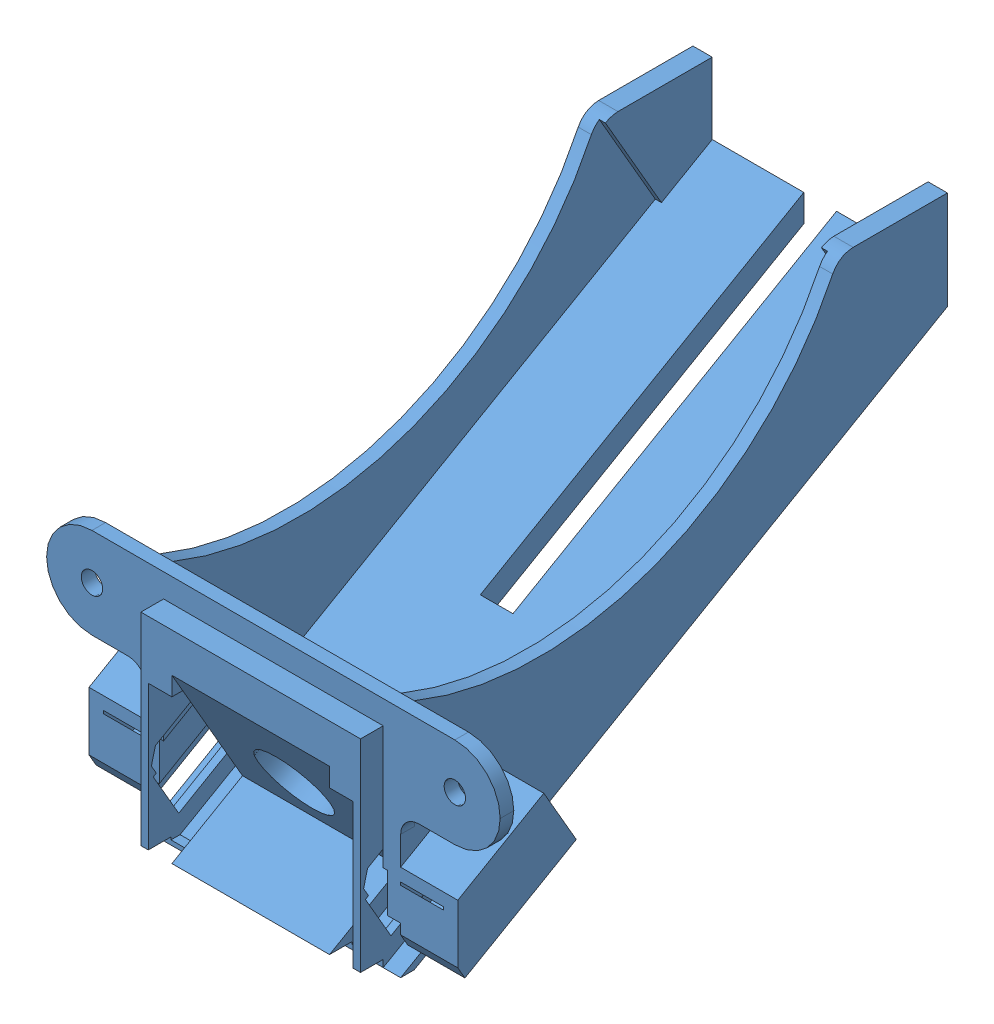
SolidWorks assembly bottleMountAssembly, configuration Default. Lengths in mm.
Overall size (63.5 56.87 79.72).
6 component instances, 5 part files, 12 mates.
Components (placement in the parent):
- bottle-1: bottle [Default] at (-0.6948 217.1065 -36.0917) x (0.0057 -0.258799 -0.965914) z (-0.999968 -0.006981 -0.00403) (suppressed, hidden)
- bottlePivot-1: bottlePivot [NewBottle] at (0.2137 47.0768 17.3511) x (-1 0 0) z (0 0.5 -0.866025) (suppressed, hidden)
- bottleMount-1: bottleMount [external_ir] at (0.2137 51.4957 48.6286) size (63.5 56.87 79.72)
- irOutline_sparkfun-3: irOutline_sparkfun [Default] at (-15.7593 31.9593 48.5354) x (0 0.866025 0.5) z (1 0 0) (suppressed, hidden)
- irOutline_sparkfun-4: irOutline_sparkfun [Default] at (16.1867 31.9593 48.5354) x (0 -0.866025 -0.5) z (-1 0 0) (suppressed, hidden)
- M3x12-1: M3x12 [90751A113] at (0.2137 70.9615 25.6416) x (-0.951128 0.154398 -0.267426) z (0 -0.866025 -0.5) (suppressed, hidden)
Mates (geometry in assembly coordinates):
- Coincident2: coincident anti-aligned: plane of bottlePivot-1 through (0.2137 51.8393 9.1022) normal (0 -0.866025 -0.5); plane of bottleMount-1 through (-14.8993 34.638 38.8958) normal (0 0.866025 0.5)
- Coincident3: coincident anti-aligned: plane of bottlePivot-1 through (-2.0723 48.6643 14.6015) normal (-1 0 0); plane of bottleMount-1 through (-2.0723 -0.5281 18.5926) normal (1 0 0)
- Coincident4: coincident anti-aligned: plane of bottleMount-1 through (-14.8993 34.638 38.8958) normal (0 0.866025 0.5); plane of irOutline_sparkfun-3 through (-11.4593 29.7942 47.2854) normal (0 -0.866025 -0.5)
- Coincident5: coincident anti-aligned: plane of bottleMount-1 through (0.2137 45.402 59.1833) normal (0 0.5 -0.866025); plane of irOutline_sparkfun-3 through (-11.4593 30.7093 50.7005) normal (0 -0.5 0.866025)
- Coincident6: coincident anti-aligned: plane of bottleMount-1 through (-15.7593 79.1474 -21.9031) normal (1 0 0); plane of irOutline_sparkfun-3 through (-15.7593 31.9593 48.5354) normal (-1 0 0)
- Coincident7: coincident anti-aligned: plane of bottleMount-1 through (-14.8993 34.638 38.8958) normal (0 0.866025 0.5); plane of irOutline_sparkfun-4 through (11.8867 29.7942 47.2854) normal (0 -0.866025 -0.5)
- Coincident8: coincident anti-aligned: plane of bottleMount-1 through (0.2137 45.402 59.1833) normal (0 0.5 -0.866025); plane of irOutline_sparkfun-4 through (11.8867 30.7093 50.7005) normal (0 -0.5 0.866025)
- Coincident9: coincident anti-aligned: plane of bottleMount-1 through (16.1867 79.1474 -21.9031) normal (-1 0 0); plane of irOutline_sparkfun-4 through (16.1867 31.9593 48.5354) normal (1 0 0)
- LimitDistance1: limit distance = 4.911 mm anti-aligned: plane of bottlePivot-1 through (-25.1863 35.3293 37.6984) normal (0 -0.5 0.866025); plane of irOutline_sparkfun-3 through (-11.4593 36.7093 40.3082) normal (0 0.5 -0.866025)
- Concentric1: concentric anti-aligned: cylinder of bottle-1 through (0.2137 38.6654 47.5801) axis (0 0.5 -0.866025) radius 5; cylinder of bottlePivot-1 through (0.2137 58.6203 13.0172) axis (0 -0.5 0.866025) radius 5.08
- Concentric2: concentric aligned: cylinder of bottlePivot-1 through (0.2137 36.589 5.7966) axis (0 0.866025 0.5) radius 1.4; line of M3x12-1 through (0.2137 57.7581 18.0186) axis (0 0.866025 0.5)
- Tangent1: tangent anti-aligned: cylinder of bottle-1 through (0.2137 38.6654 47.5801) axis (0 0.5 -0.866025) radius 5; plane of M3x12-1 through (0.6769 61.2825 18.4061) normal (0 -0.866025 -0.5)
